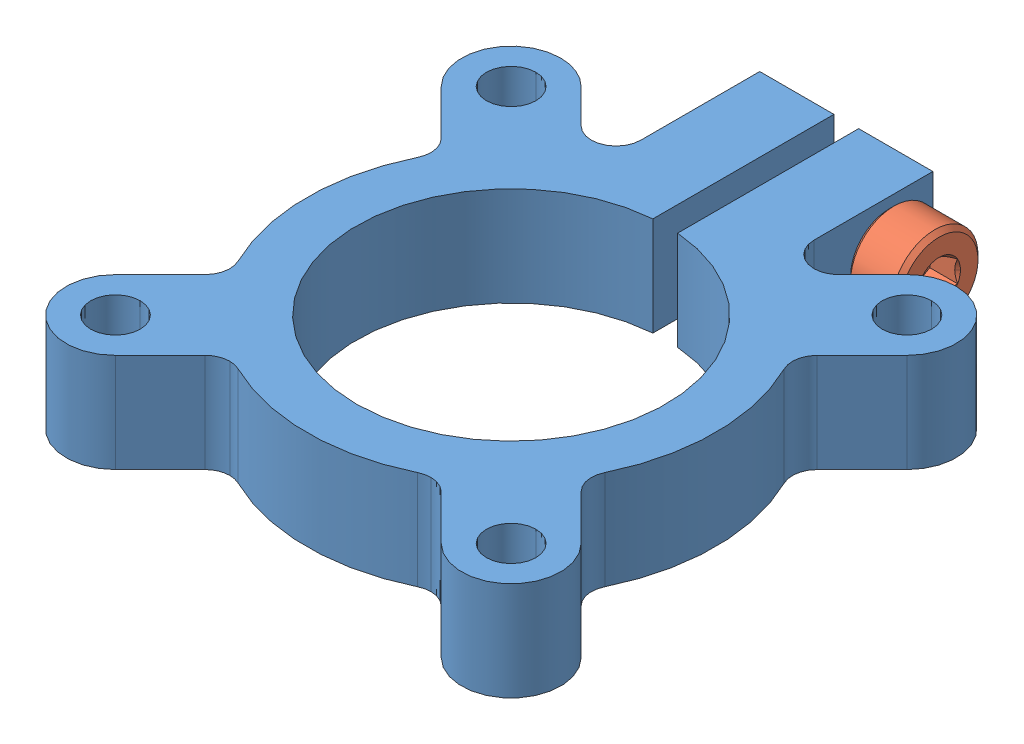
SolidWorks assembly 25mm Clamping Hub 1305-0032-0025, configuration Default. Lengths in mm.
Overall size (40 8 47.1).
2 component instances, 2 part files, 0 mates.
Components (placement in the parent):
- 1305-0032-0025.STEP-1: 1305-0032-0025.STEP [Default] at (-37.9952 28.0173 1.8474) size (40 8 47.1)
- 2800-0004-0014_90128A207.STEP-1: 2800-0004-0014_90128A207.STEP [Default] at (-44.9952 32.0173 -21.7526) x (0 0 1) z (-1 0 0) size (7 7 18.01)
